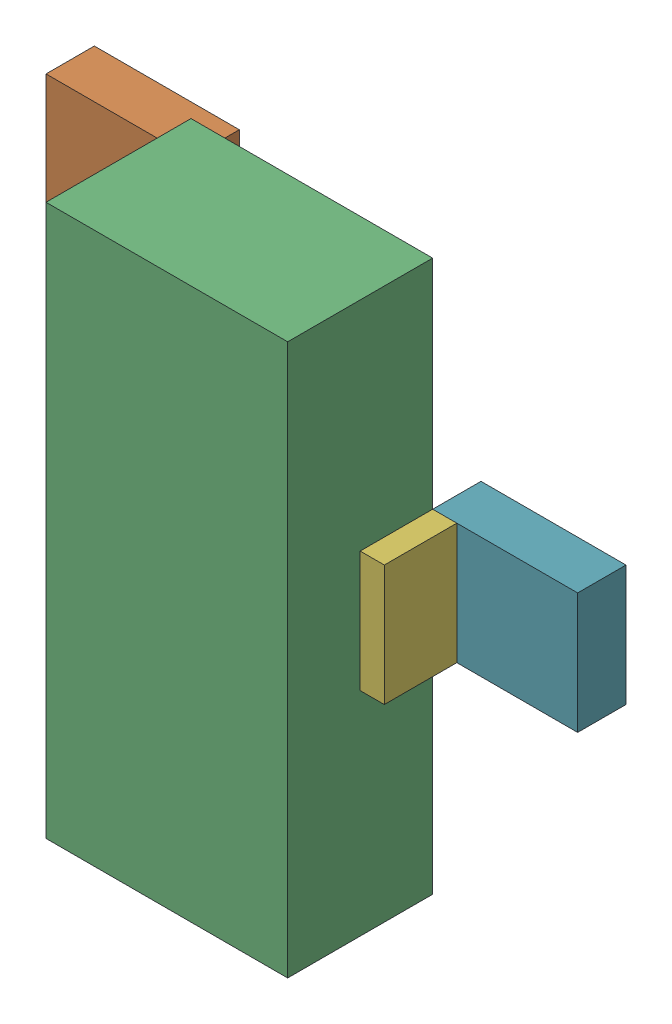
SolidWorks assembly Q2, configuration Default. Lengths in mm.
Overall size (2.79 2.9 1.02).
14 component instances, 3 part files, 0 mates.
Components (placement in the parent):
- 898052496-1: 898052496 [Default] at (35.6409 12.5831 0) size (0.76 0.64 0.25)
  - Extruded_10-1: Extruded_10 [Default] at origin size (0.76 0.64 0.25)
- 898052496-2: 898052496 [Default] at (35.6409 14.4881 0) size (0.76 0.64 0.25)
  - Extruded_10-1: Extruded_10 [Default] at origin size (0.76 0.64 0.25)
- 898052360-1: 898052360 [Default] at (36.6569 13.5356 0.254) size (1.27 2.9 0.76)
  - Extruded_11-1: Extruded_11 [Default] at origin size (1.27 2.9 0.76)
- 898052632-1: 898052632 [Default] at (35.9584 12.5831 0.254) size (0.13 0.64 0.38)
  - Extruded_12-1: Extruded_12 [Default] at origin size (0.13 0.64 0.38)
- 898052632-2: 898052632 [Default] at (35.9584 14.4881 0.254) size (0.13 0.64 0.38)
  - Extruded_12-1: Extruded_12 [Default] at origin size (0.13 0.64 0.38)
- 898052632-3: 898052632 [Default] at (37.3554 13.5229 0.254) size (0.13 0.64 0.38)
  - Extruded_12-1: Extruded_12 [Default] at origin size (0.13 0.64 0.38)
- 898052496-3: 898052496 [Default] at (37.6728 13.5229 0) size (0.76 0.64 0.25)
  - Extruded_10-1: Extruded_10 [Default] at origin size (0.76 0.64 0.25)
